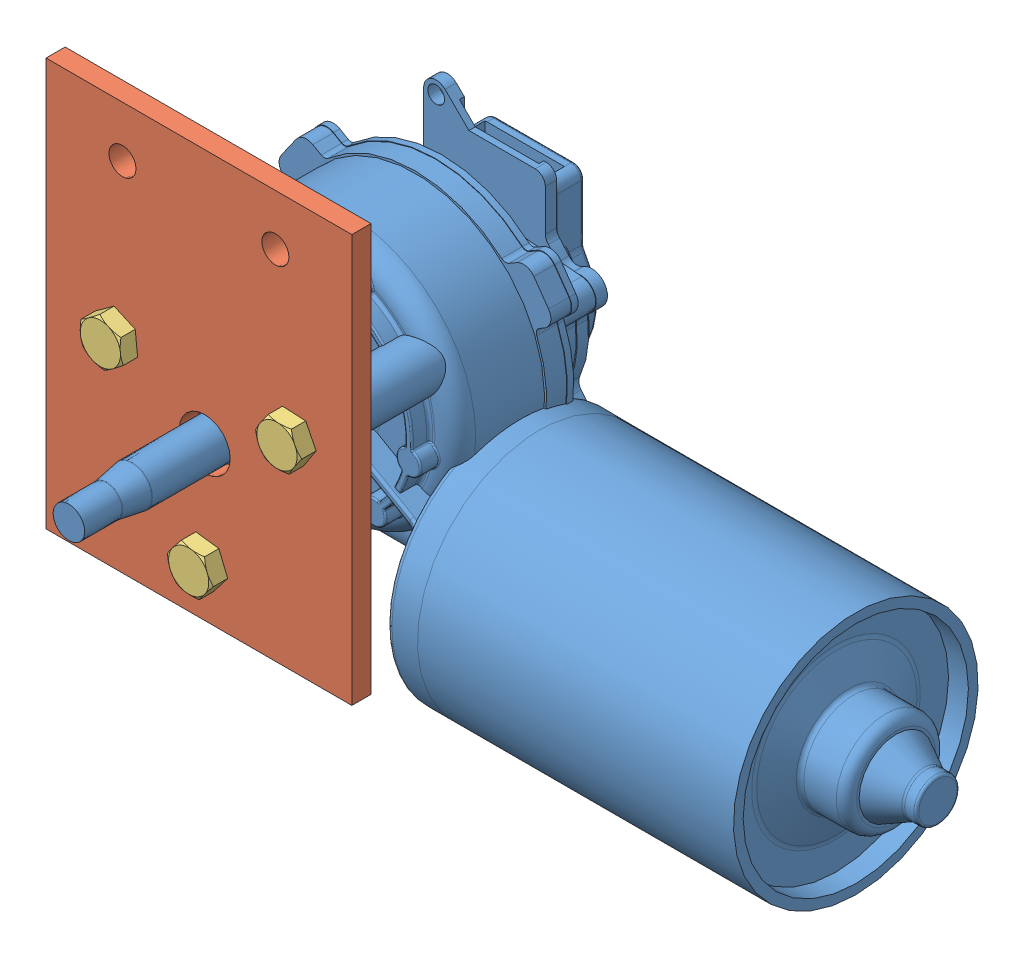
SolidWorks assembly motor bracket assembly, configuration Default. Lengths in mm.
Overall size (175.66 126.24 116.01).
5 component instances, 3 part files, 9 mates.
Components (placement in the parent):
- 44 RPM Entstort Right Angle Gear Motor-1: 44 RPM Entstort Right Angle Gear Motor [Default] at (75.065 73.1836 102.1742) size (170.1 101.53 116.01)
- bracket motor mount-1: bracket motor mount [Default] at (-21.7871 168.9416 143.9572) x (0 -1 0) z (0 0 1) size (101.6 76.2 4.76)
- M6X1mm-10mm Hex Head-1: M6X1mm-10mm Hex Head [91287A133] at (39.7568 118.1416 145.7197) x (0 0 -1) z (-0.053654 -0.99856 0) size (14 11.55 10)
- M6X1mm-10mm Hex Head-2: M6X1mm-10mm Hex Head [91287A133] at (-4.2372 118.1416 145.7197) x (0 0 -1) z (0.587181 -0.809455 0) size (14 11.55 10)
- M6X1mm-10mm Hex Head-3: M6X1mm-10mm Hex Head [91287A133] at (17.7598 80.0416 145.7197) x (0 0 -1) z (0.923728 0.383049 0) size (14 11.55 10)
Mates (geometry in assembly coordinates):
- Concentric1: concentric aligned: cylinder of 44 RPM Entstort Right Angle Gear Motor-1 through (17.7598 105.4416 182.5652) axis (0 0 1) radius 5; circle of bracket motor mount-1
- Concentric2: concentric anti-aligned: cone of 44 RPM Entstort Right Angle Gear Motor-1 through (39.7568 118.1416 143.3222) axis (0 0 -1); circle of bracket motor mount-1
- Coincident2: coincident anti-aligned: plane of 44 RPM Entstort Right Angle Gear Motor-1; plane of bracket motor mount-1 through (-21.7871 168.9416 143.9572) normal (0 0 -1)
- Concentric4: concentric aligned: circle of bracket motor mount-1; circle of M6X1mm-10mm Hex Head-1
- Coincident5: coincident anti-aligned: plane of bracket motor mount-1 through (-21.7871 168.9416 148.7197) normal (0 0 1); plane of M6X1mm-10mm Hex Head-1 through (37.1425 123.2893 148.7197) normal (0 0 -1)
- Concentric5: concentric aligned: circle of bracket motor mount-1; cone of M6X1mm-10mm Hex Head-2 through (-4.2372 118.1416 152.7197) axis (0 0 1)
- Coincident9: coincident anti-aligned: plane of bracket motor mount-1 through (-21.7871 168.9416 148.7197) normal (0 0 1); plane of M6X1mm-10mm Hex Head-2 through (-9.5099 120.4938 148.7197) normal (0 0 -1)
- Concentric6: concentric aligned: circle of bracket motor mount-1; circle of M6X1mm-10mm Hex Head-3
- Coincident10: coincident anti-aligned: plane of bracket motor mount-1 through (-21.7871 168.9416 148.7197) normal (0 0 1); plane of M6X1mm-10mm Hex Head-3 through (14.2469 75.4598 148.7197) normal (0 0 -1)
